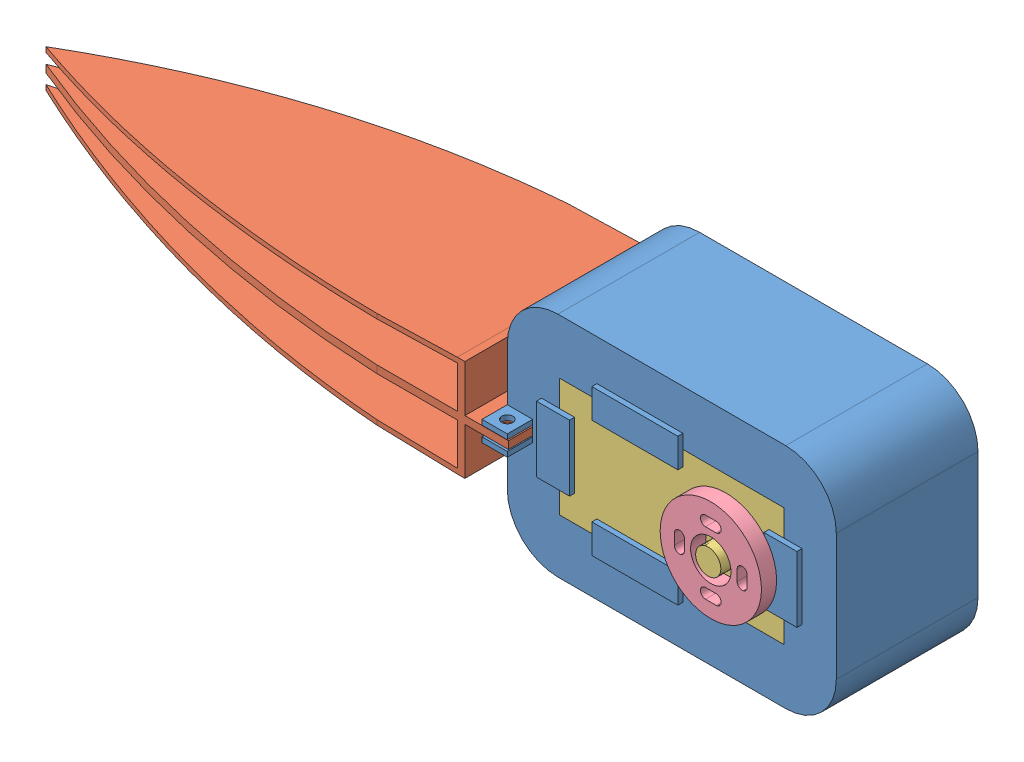
SolidWorks assembly link7, configuration 預設. Lengths in mm.
Overall size (170.1 45 38.21).
5 component instances, 4 part files, 12 mates.
Components (placement in the parent):
- bus2_tail-2: bus2_tail [預設] at (-9.0934 -16.9047 37.067) size (65 45 38)
- bus_final_tail-2: bus_final_tail [預設] at (-73.1187 -16.9047 50.3365) x (-1 0 0.00071) z (0 1 0) size (110.1 38.13 25.31)
- bus_servo-4: bus_servo [預設] at (-16.5803 -28.3978 37.067) x (1 0 0) z (0 -1 0) size (44.4 38 23.4)
- bus_servo_cicrcle1-1: bus_servo_cicrcle1 [預設] at (-24.328 -16.9047 66.567) size (20 20 3)
- bus_servo_cicrcle1-2: bus_servo_cicrcle1 [預設] at (-24.328 -16.9047 32.567) size (20 20 3)
Mates (geometry in assembly coordinates):
- 重合/共線/共點11: coincident: plane of bus2_tail-2 through (-58.728 -28.6047 76.067) normal (0 1 0); plane of bus_servo-4 through (-58.728 -28.6047 65.067) normal (0 -1 0)
- 重合/共線/共點12: coincident: plane of bus2_tail-2 through (-14.328 -5.2047 76.067) normal (-1 0 0); plane of bus_servo-4 through (-14.328 -5.2047 65.067) normal (1 0 0)
- 重合/共線/共點13: coincident: plane of bus2_tail-2 through (-9.0934 -16.9047 65.067) normal (0 0 1); plane of bus_servo-4 through (-16.5803 -28.3978 65.067) normal (0 0 1)
- 同軸心6: concentric: cylinder of bus2_tail-2 through (-66.528 -11.9047 67.567) axis (0 -1 0) radius 1.1; cylinder of bus_final_tail-2 through (-66.528 -17.6547 67.567) axis (0 1 0) radius 1.1
- 同軸心7: concentric: cylinder of bus2_tail-2 through (-66.528 -11.9047 34.567) axis (0 -1 0) radius 1.1; cylinder of bus_final_tail-2 through (-66.528 -17.6547 34.567) axis (0 1 0) radius 1.1
- 平行相距7: distance = 0.25 mm: plane of bus_final_tail-2 through (-73.1187 -17.6547 50.3365) normal (0 -1 0); plane of bus2_tail-2 through (-9.0934 -17.9047 37.067) normal (0 1 0)
- 同軸心9: concentric: cylinder of bus_servo-4 through (-24.328 -16.9047 65.067) axis (0 0 1) radius 2.5; cylinder of bus_servo_cicrcle1-1 through (-24.328 -16.9047 70.567) axis (0 0 -1) radius 4
- 平行4: parallel: plane of bus2_tail-2 through (-4.028 5.5953 65.067) normal (1 0 0); plane of bus_servo_cicrcle1-1 through (-17.128 -15.8547 70.567) normal (-1 0 0)
- 平行相距8: distance = 0.5 mm: plane of bus_servo-4 through (-24.328 -16.9047 70.067) normal (0 0 1); plane of bus_servo_cicrcle1-1 through (-24.328 -16.9047 69.567) normal (0 0 1)
- 同軸心10: concentric: cylinder of bus_servo-4 through (-24.328 -16.9047 32.067) axis (0 0 1) radius 2.5; cylinder of bus_servo_cicrcle1-2 through (-24.328 -16.9047 36.567) axis (0 0 -1) radius 4
- 平行5: parallel: plane of bus2_tail-2 through (-4.028 5.5953 65.067) normal (1 0 0); plane of bus_servo_cicrcle1-2 through (-17.128 -15.8547 36.567) normal (-1 0 0)
- 平行相距10: distance = 0.5 mm: plane of bus_servo-4 through (-24.328 -16.9047 32.067) normal (0 0 -1); plane of bus_servo_cicrcle1-2 through (-24.328 -16.9047 32.567) normal (0 0 -1)
